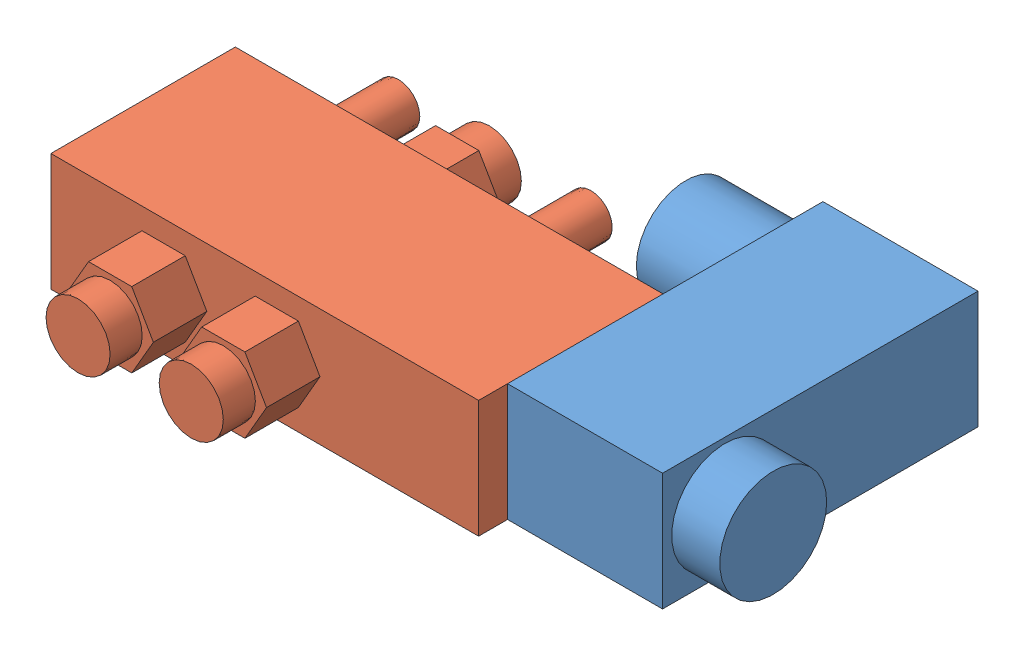
SolidWorks assembly Solenoid_assembly_v1, configuration Default. Lengths in mm.
Overall size (118 22 82).
2 component instances, 2 part files, 6 mates.
Components (placement in the parent):
- Solenoid_elex_v1-1: Solenoid_elex_v1 [Default] at (0 22 0) x (-1 0 0) z (0 0 1) size (56 22 60.59)
- Solenoid_air_v1-1: Solenoid_air_v1 [Default] at (0 0 -29.0875) x (-1 0 0) z (0 0 -1) size (80 22 67.5)
Mates (geometry in assembly coordinates):
- Coincident2: coincident anti-aligned: plane of Solenoid_elex_v1-1 through (0 0 0) normal (0 -1 0)
- Coincident3: coincident aligned: plane of Solenoid_elex_v1-1 through (0 0 0) normal (0 0 1)
- Coincident4: coincident anti-aligned: plane of Solenoid_elex_v1-1 through (0 0 0) normal (-1 0 0)
- Coincident6: coincident aligned: plane of Solenoid_elex_v1-1 through (0 22 0) normal (0 1 0); plane of Solenoid_air_v1-1 through (0 22 -29.0875) normal (0 1 0)
- Coincident7: coincident anti-aligned: plane of Solenoid_elex_v1-1 through (0 0 0) normal (-1 0 0); plane of Solenoid_air_v1-1 through (0 22 5.4125) normal (1 0 0)
- Distance1: distance = 13 mm: plane of Solenoid_air_v1-1 through (0 22 -29.0875) normal (0 0 -1); cylinder of Solenoid_elex_v1-1 through (-18 11 -51.3375) axis (1 0 0) radius 9.25
